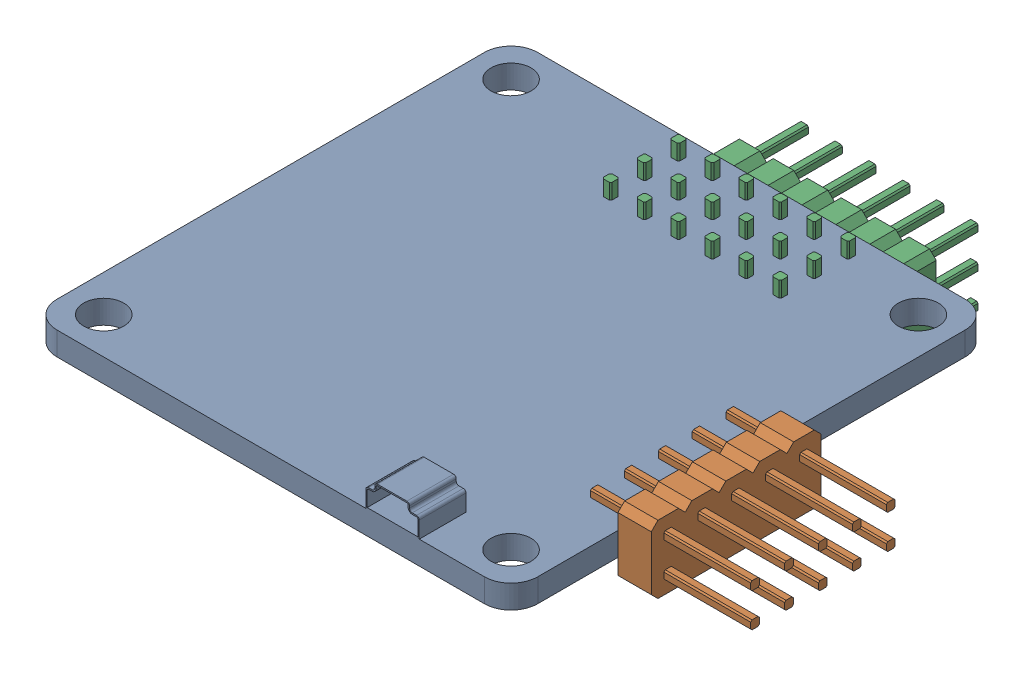
SolidWorks assembly assembly 1, configuration Default. Lengths in mm.
Overall size (45 11.52 43.91).
3 component instances, 3 part files, 12 mates.
Components (placement in the parent):
- distribution board-2: distribution board [Default] at (-11.94 -1.0842 5.7633) size (36 3.75 36)
- electric unit-1: electric unit [Default] at (3.06 1.0608 14.4933) x (0 -1 0) z (0 0 1) size (5.08 12 12.7)
- electrical unit 2-2: electrical unit 2 [Default] at (-3.21 1.8208 -5.6657) x (0 0 -1) z (-1 0 0) size (14.8 10.68 15.24)
Mates (geometry in assembly coordinates):
- Width1: width anti-aligned: plane of distribution board-2 through (4.06 -1.0842 21.7633) normal (0 -1 0); plane of distribution board-2 through (4.06 0.6658 21.7633) normal (0 1 0); plane of electric unit-1 through (15.06 -1.1542 14.2683) normal (0 1 0); plane of electric unit-1 through (15.06 0.7358 14.2683) normal (0 -1 0)
- Coincident1: coincident anti-aligned: plane of distribution board-2 through (6.06 0.6658 -10.2367) normal (1 0 0); plane of electric unit-1 through (6.06 1.0608 14.4933) normal (-1 0 0)
- Distance2: distance = 8 mm aligned: plane of electric unit-1 through (8.56 -2.2492 15.7633) normal (0 0 1); plane of distribution board-2 through (-27.94 0.6658 23.7633) normal (0 0 1)
- Parallel1: parallel aligned: plane of distribution board-2 through (-27.94 0.6658 23.7633) normal (0 0 1); plane of electrical unit 2-1 through (-32.74 -1.7342 11.0033) normal (0 0 1)
- Parallel2: parallel aligned: plane of distribution board-2 through (-29.94 0.6658 -10.2367) normal (-1 0 0); plane of electrical unit 2-1 through (-32.74 1.8208 -2.9667) normal (-1 0 0)
- Distance5: distance = 0.3 mm anti-aligned: plane of electrical unit 2-1 through (-30.24 1.8208 -2.9667) normal (1 0 0); plane of distribution board-2 through (-29.94 0.6658 -10.2367) normal (-1 0 0)
- Distance6: distance = 8 mm aligned: plane of distribution board-2 through (-27.94 0.6658 -12.2367) normal (0 0 -1); plane of electrical unit 2-1 through (-32.74 -1.7342 -4.2367) normal (0 0 -1)
- Distance8: distance = 1.9 mm aligned: plane of distribution board-2 through (4.06 0.6658 21.7633) normal (0 1 0); plane of electrical unit 2-1 through (-32.74 -1.2342 1.3433) normal (0 1 0)
- Parallel3: parallel: plane of distribution board-2 through (-29.94 0.6658 -10.2367) normal (-1 0 0); plane of electrical unit 2-2 through (-17.18 -2.75 -16.0707) normal (-1 0 0)
- Parallel4: parallel: plane of distribution board-2 through (-27.94 0.6658 -12.2367) normal (0 0 -1); plane of electrical unit 2-2 through (-3.21 0.805 -16.0707) normal (0 0 -1)
- Distance11: distance = 8 mm: plane of electrical unit 2-2 through (-1.94 -1.7342 -16.0707) normal (1 0 0); plane of distribution board-2 through (6.06 0.6658 -10.2367) normal (1 0 0)
- Distance12: distance = 1.9 mm aligned: plane of electrical unit 2-2 through (-15.14 -1.2342 -16.0707) normal (0 1 0); plane of distribution board-2 through (4.06 0.6658 21.7633) normal (0 1 0)
